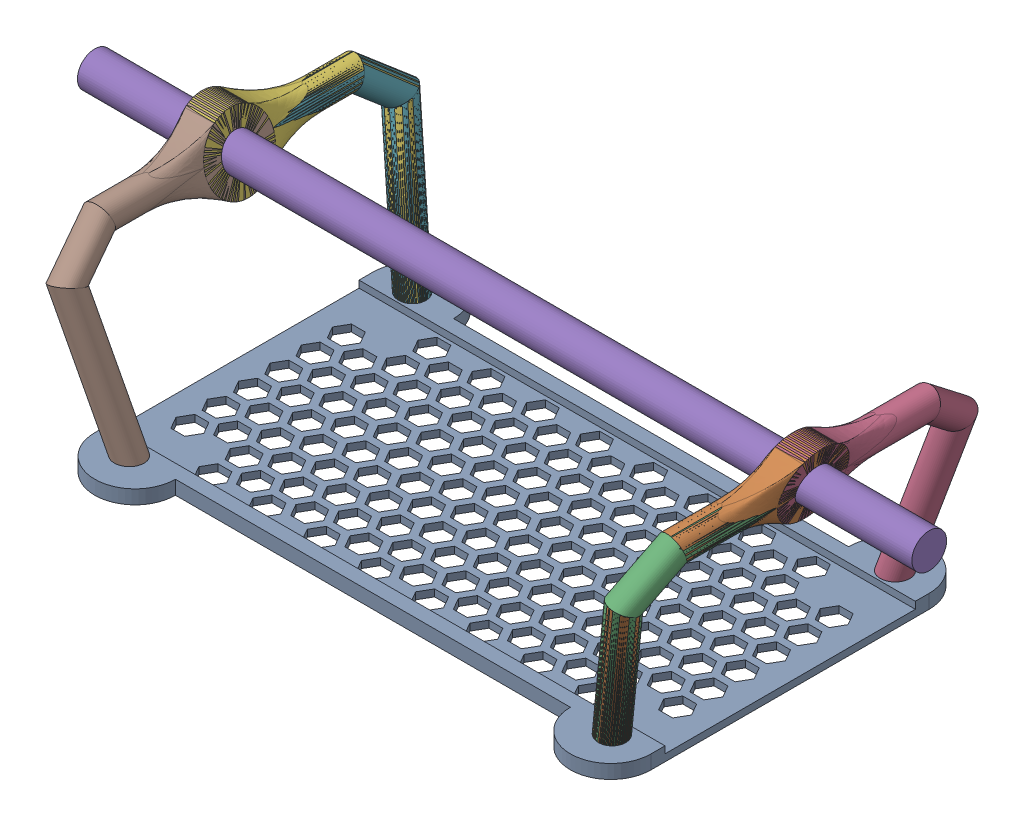
SolidWorks assembly ensamble, configuration Default. Lengths in mm.
Overall size (120 34.3 52.25).
4 component instances, 3 part files, 8 mates.
Components (placement in the parent):
- cabina_2-1: cabina_2 [Default] at (0.3064 0.6665 -1.2939) size (80 2 51.6)
- cabina_arc-1: cabina_arc [Default] at (32.3987 -7.4953 -1.2939) x (0 0 -1) z (0.968235 -0.250042 0) size (52.25 34.39 4)
- cabina_eje-1: cabina_eje [Default] at (60.3064 27.9657 -1.2939) x (0 0 1) z (-1 0 0) size (5 5 120)
- cabina_arc-2: cabina_arc [Default] at (-31.7858 -7.4953 -1.2939) x (0 0 1) z (-0.968235 -0.250042 0) size (52.25 34.39 4)
Mates (geometry in assembly coordinates):
- Coincidente1: coincident: plane of cabina_2-1 through (0.3064 0.6665 -1.2939) normal (0 -1 0); plane of cabina_arc-1 through (54.5064 0.6665 16.5984) normal (0 -1 0)
- Coincidente2: coincident: point of cabina_2-1; point of cabina_arc-1
- Coincidente3: coincident: point of cabina_2-1; point of cabina_arc-1
- Coincidente4: coincident: plane of cabina_2-1 through (0.3064 0.6665 -1.2939) normal (0 -1 0); plane of cabina_arc-2 through (-13.8936 0.6665 -23.4016) normal (0 -1 0)
- Coincidente5: coincident: point of cabina_2-1; point of cabina_arc-2
- Coincidente6: coincident: point of cabina_2-1; point of cabina_arc-2
- Concéntrica1: concentric: cylinder of cabina_eje-1 through (-29.4647 27.9657 -1.2939) axis (1 0 0) radius 2.5; cylinder of cabina_arc-2 through (-35.9434 27.9657 -1.2939) axis (-1 0 0) radius 2.51
- Paralelo1: distance = 20 mm aligned: plane of cabina_eje-1 through (60.3064 27.9657 -1.2939) normal (1 0 0); plane of cabina_2-1 through (40.3064 1.6665 -1.2939) normal (1 0 0)
